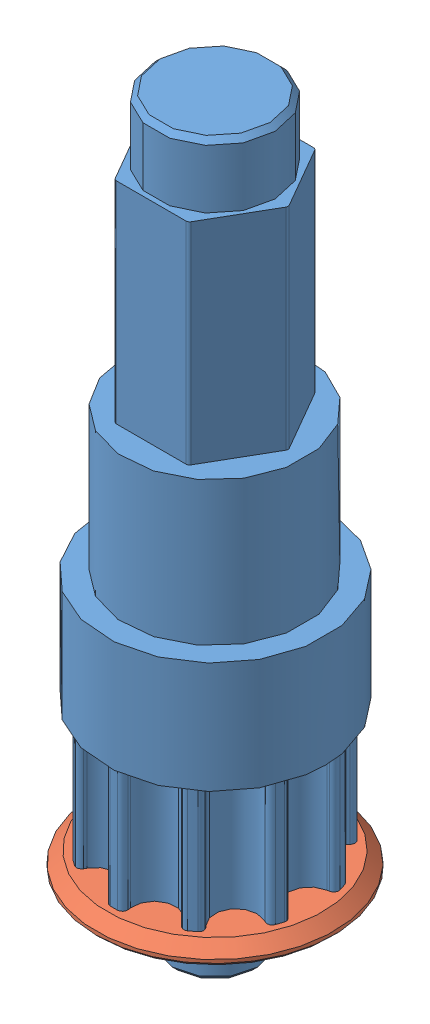
SolidWorks assembly MK2 Steering Shaft V3 Assembly, configuration Default. Lengths in mm.
Overall size (17.78 55.56 17.78).
2 component instances, 2 part files, 0 mates.
Components (placement in the parent):
- MK2 Steering Shaft V3-1: MK2 Steering Shaft V3 [Default] at origin size (16.51 55.56 16.51)
- MK2 Steering Shaft V3, Pulley Flange-1: MK2 Steering Shaft V3, Pulley Flange [Default] at (0 -51.0159 0) size (17.78 1.85 17.78)
